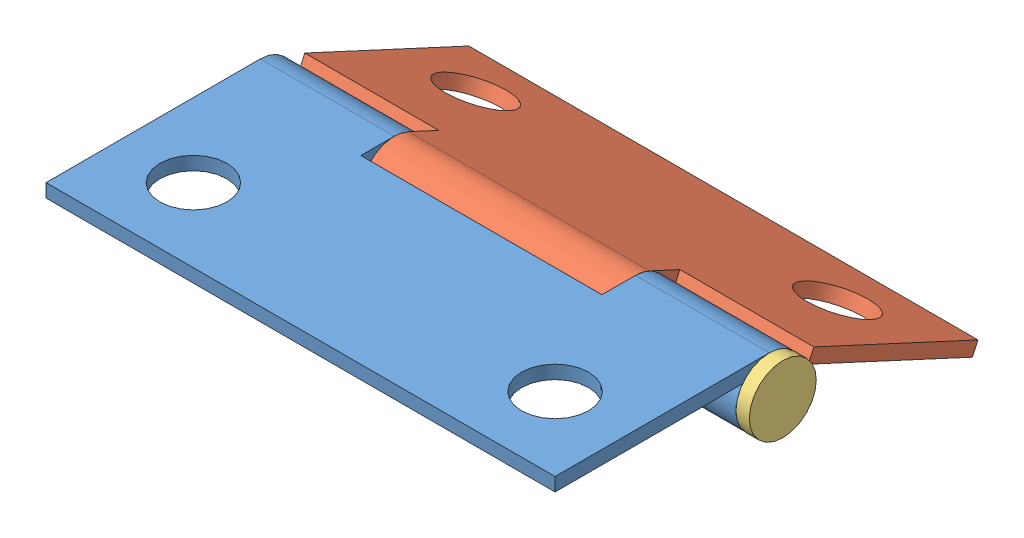
SolidWorks assembly Assem1, configuration Default. Lengths in mm.
Overall size (39 12.31 31.57).
3 component instances, 3 part files, 2 mates.
Components (placement in the parent):
- Outside Plate-1: Outside Plate [Default] at (-16.9893 2.5504 7.2323) size (38 5 18.5)
- Inside Plate-1: Inside Plate [Default] at (21.0107 -4.3109 -23.9171) x (-1 0 0) z (0 -0.420155 -0.907452) size (38 5 18.5)
- Pin-1: Pin [Default] at (22.0107 1.0504 -8.7677) x (0 1 0) z (0 0 1) size (5 39 5)
Mates (geometry in assembly coordinates):
- Hinge1: hinge anti-aligned: cylinder of Inside Plate-1 through (-16.9893 1.0504 -8.7677) axis (1 0 0) radius 1.5; cylinder of Outside Plate-1 through (21.0107 1.0504 -8.7677) axis (-1 0 0) radius 1.5; plane of Inside Plate-1 through (-6.9893 -2.2686 -9.9859) normal (-1 0 0); plane of Outside Plate-1 through (-6.9893 -1.4496 -6.2677) normal (1 0 0)
- Hinge2: hinge anti-aligned: cylinder of Outside Plate-1 through (21.0107 1.0504 -8.7677) axis (-1 0 0) radius 1.5; cylinder of Pin-1 through (-16.9893 1.0504 -8.7677) axis (1 0 0) radius 1.5; plane of Pin-1 through (21.0107 1.0504 -8.7677) normal (-1 0 0); plane of Outside Plate-1 through (21.0107 1.0504 -8.7677) normal (1 0 0)
